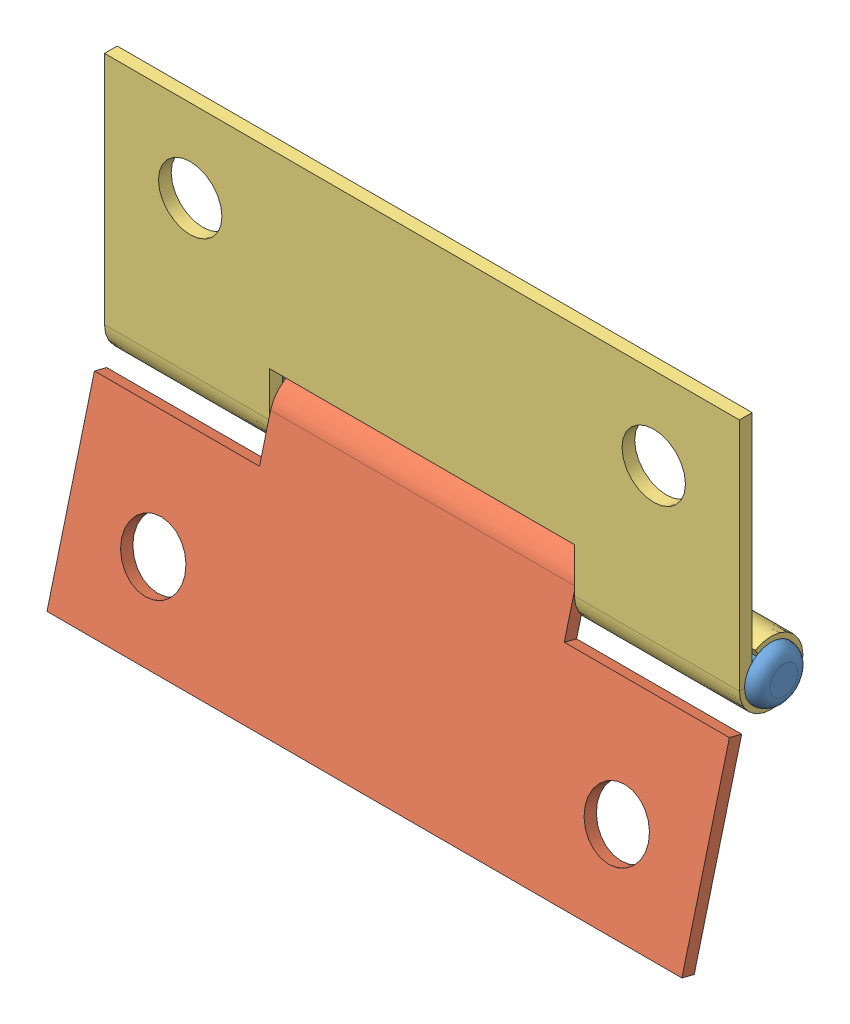
SolidWorks assembly Hinge, configuration Default. Lengths in mm.
Overall size (52 37.04 10.07).
3 component instances, 3 part files, 6 mates.
Components (placement in the parent):
- Pin-1: Pin [Default] at (-19.3424 -18.5 -2.5) x (1 0 0) z (0 0.540208 0.841532) size (52 4.2 4.2)
- Wing 1-1: Wing 1 [Default] at (6.6576 -25.8741 0.9457) x (1 0 0) z (0 0.96847 -0.249129) size (50 5 21)
- Wing 2-1: Wing 2 [Default] at (6.6576 -10.5 -1) x (-1 0 0) z (0 -1 0) size (50 5 21)
Mates (geometry in assembly coordinates):
- Concentric2: concentric anti-aligned: cylinder of Pin-1 through (31.6576 -18.5 -2.5) axis (-1 0 0) radius 1.5; cylinder of Wing 1-1 through (31.6576 -18.5 -2.5) axis (1 0 0) radius 1.5
- Distance1: distance = 13 mm anti-aligned: plane of Wing 1-1 through (18.6576 -21.2668 0.7931) normal (1 0 0); plane of Pin-1 through (31.6576 -18.5 -2.5) normal (-1 0 0)
- Concentric3: concentric aligned: cylinder of Pin-1 through (31.6576 -18.5 -2.5) axis (-1 0 0) radius 1.5; cylinder of Wing 2-1 through (-18.3424 -18.5 -2.5) axis (-1 0 0) radius 1.5
- Coincident2: coincident anti-aligned: plane of Pin-1 through (31.6576 -18.5 -2.5) normal (-1 0 0); plane of Wing 2-1 through (31.6576 -18.5 -2.5) normal (1 0 0)
- Coincident3: coincident aligned: plane of Wing 2-1 through (-18.3424 -21 0) normal (0 0 1)
- Coincident4: coincident aligned: plane of Wing 2-1 through (31.6576 0 0) normal (0 1 0)
